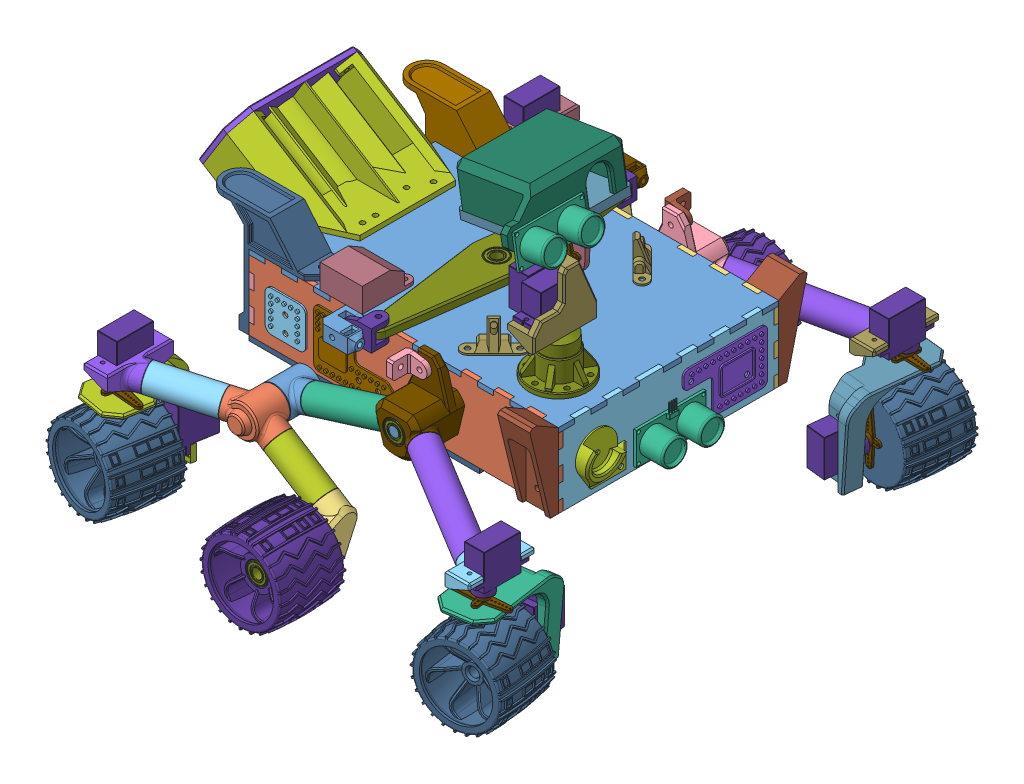
SolidWorks assembly full, configuration Default. Lengths in mm.
Overall size (307.73 234.76 324.89).
113 component instances, 62 part files, 10 mates.
Components (placement in the parent):
- bodySub-2-1: bodySub-2 [Default] at (-27.7012 6.4146 93.6508) size (271.51 168.8 196)
  - body-top-1: body-top [Default] at (-43.052 0 151.6865) x (1 0 0) z (0 1 0) size (191 136 3)
  - body-right-1: body-right [Default] at (-43.052 -43 148.6865) size (191 46 3)
  - body-left-1: body-left [Default] at (-43.052 -43 18.6865) x (-1 0 0) z (0 0 -1) size (191 46 3)
  - body-rear-1: body-rear [Default] at (-43.052 -43 15.6865) x (0 0 -1) z (1 0 0) size (136 46 3)
  - body-front-1: body-front [Default] at (147.948 -43 15.6865) x (0 0 1) z (-1 0 0) size (136 46 3)
  - usSensor-1: usSensor [Default] at (-46.052 -45.55 62.1865) x (0 0 1) z (0 -1 0) size (43 15.6 26)
  - usSensor-2: usSensor [Default] at (147.948 -21 62.1865) x (0 0 1) z (0 1 0) size (43 15.6 26)
  - power-1: power [Default] at (-43.052 -43 151.6865) x (0 0 1) z (-1 0 0) size (84 85.03 90.67)
  - powerCap-1: powerCap [Default] at (-74.8205 44.2822 15.6865) x (0 0 -1) z (-0.848048 0.529919 0) size (84 51.88 5)
  - powerShoulder-left-1: powerShoulder-left [Default] at (-43.052 -43 15.6865) x (-1 0 0) z (0 0 -1) size (66.06 69 21)
  - powerShoulder-right-1: powerShoulder-right [Default] at (-43.052 -43 109.6865) x (-1 0 0) z (0 0 -1) size (66.06 69 21)
  - shoulder-1: shoulder [Default] at (127.948 -43 151.6865) size (20 53.5 17.6)
  - shoulder-2: shoulder [Default] at (147.948 -43 15.6865) x (-1 0 0) z (0 0 -1) size (20 53.5 17.6)
  - headSub-1: headSub [Default] at (131.8571 34.2972 110.6077) size (71.32 113.8 76.5) (flexible)
    - headServoMount-1: headServoMount [Default] at (-5.7591 24.2018 7.3288) x (0 0 1) z (1 0 0) size (39.75 36.12 28.6)
    - headMount-1: headMount [Default] at (-19.6139 25.1697 -5.5142) x (0.16009 -0.987102 0) z (0 0 -1) size (40 30 34)
    - headBaseplate-1: headBaseplate [Default] at (-50.728 44.8869 -23.5142) x (0 0 1) z (-0.987102 -0.16009 0) size (60 5 50)
    - headCanopy-1: headCanopy [Default] at (-6.1756 82.5045 -23.5142) x (0 0 1) z (0.16009 -0.987102 0) size (76.5 50 25)
    - usSensor-2: usSensor [Default] at (-0.5725 47.9559 49.9858) x (0 0 -1) z (0.16009 -0.987102 0) size (43 15.6 26)
    - mastMount-top-1: mastMount-top [Default] at (-11.9091 -31.2972 13.0788) size (36 28 36)
    - sg90Servo-1: sg90Servo [Default] at (-5.7591 24.0708 7.3288) x (0 0 1) z (1 0 0) size (32.7 29.37 12.3)
    - sg90Servo-2: sg90Servo [Default] at (-18.0591 24.5458 25.4538) x (0 -1 0) z (1 0 0) size (32.7 29.37 12.3)
    - sg90ServoHorn-star-1: sg90ServoHorn-star [Default] at (-27.3265 20.2151 -5.5142) x (0.16009 -0.987102 0) z (-0.987102 -0.16009 0) size (34.4 4 15.7)
  - pivotAxle-1: pivotAxle [Default] at (76.448 -20 181.6865) x (-0.972905 0.231206 0) z (-0.231206 -0.972905 0) size (6 196 6)
  - edison-arduino-1: edison-arduino [Default] at (-30.752 -13.38 66.6865) x (1 0 0) z (0 0 -1) size (127.2 12.67 72)
  - diffMount-mid-1: diffMount-mid [Default] at (-43.052 0 151.6865) x (-1 0 0) z (0 -1 0) size (30 30 3)
  - diffMount-bottom-1: diffMount-bottom [Default] at (-43.052 -3 151.6865) x (-1 0 0) z (0 -1 0) size (30 30 3)
  - sideDetailA-left-1: sideDetailA-left [Default] at (-43.052 -43 15.6865) x (-1 0 0) z (0 0 -1) size (25 25 2)
  - sideDetailB-1: sideDetailB [Default] at (-43.052 -43 15.6865) x (-1 0 0) z (0 0 -1) size (55 35 2)
  - fontDetailA-1: fontDetailA [Default] at (147.948 -43 15.6865) x (0 0 -1) z (1 0 0) size (30.16 30.17 9.09)
  - frontDetailB-1: frontDetailB [Default] at (147.948 -43 15.6865) x (0 0 -1) z (1 0 0) size (51.58 33 2)
  - sideDetailB-mirr-1: sideDetailB-mirr [Default] at (-43.052 -43 151.6865) x (-1 0 0) z (0 0 -1) size (55 35 2)
  - sideDetailA-left-2: sideDetailA-left [Default] at (3.948 -43 151.6865) size (25 25 2)
  - bodyUnderCover-1: bodyUnderCover [Default] at (99.148 -43 15.6865) x (1 0 0) z (0 -1 0) size (142.2 136 9)
  - underCoverMagnetMount-front-1: underCoverMagnetMount-front [Default] at (99.148 -43 15.6865) x (-1 0 0) z (0 1 0) size (7 7 11.3)
  - underCoverMagnetMount-front-2: underCoverMagnetMount-front [Default] at (89.148 -43 151.6865) x (1 0 0) z (0 1 0) size (7 7 11.3)
  - underCoverMagnetMount-front-3: underCoverMagnetMount-front [Default] at (-31.552 -43 15.6865) x (-1 0 0) z (0 1 0) size (7 7 11.3)
  - underCoverMagnetMount-front-4: underCoverMagnetMount-front [Default] at (-41.552 -43 151.6865) x (1 0 0) z (0 1 0) size (7 7 11.3)
  - topDetailA-1: topDetailA [Default] at (-43.052 3 151.6865) x (1 0 0) z (0 1 0) size (24.26 24.26 16)
  - topDetailA-2: topDetailA [Default] at (108.7154 3 168.7548) x (0 0 -1) z (0 1 0) size (24.26 24.26 16)
  - topDetailB-1: topDetailB [Default] at (-43.052 3 151.6865) x (1 0 0) z (0 1 0) size (26 34 15)
  - topDetailCA-1: topDetailCA [Default] at (-46.5393 3 149.9052) x (1 0 0) z (0 1 0) size (20.56 18.54 22.66)
  - topDetailCB-1: topDetailCB [Default] at (1.7026 61.1918 61.409) x (0.910046 -0.22774 0.34634) z (0.414508 0.5 -0.760384) size (46.65 24.53 4)
- diffSub-1: diffSub [Default] at (-10.0363 9.4146 112.9319) size (33.52 13 184.66) (flexible)
  - differentialBar-1: differentialBar [Default] at (-60.7169 0 132.4054) x (1 0 0) z (0 1 0) size (30 156 5)
  - differentialHinge-1: differentialHinge [Default] at (109.2895 6 -3.7047) x (-0.999999 0 0.001295) z (0 1 0) size (18.65 13.57 13)
  - rodHinge-diff-left-1: rodHinge-diff-left [Default] at (109.2895 0 -2.6005) size (21.11 9.1 17.1)
  - rodHinge-diff-right-1: rodHinge-diff-right [Default] at (109.2895 0 147.4113) size (21.11 9.1 17.1)
  - differentialHinge-2: differentialHinge [Default] at (109.2895 -1 132.5155) x (-0.999999 0 -0.001295) z (0 -1 0) size (18.65 13.57 13)
- suspensionSub-left[moving]-1: suspensionSub-left[moving] [Default] at (56.8042 -47.8978 160.4829) x (0 0 1) z (-1 0 0) size (94.09 136.27 295.91) (flexible)
  - bogieJointFixed-left-1: bogieJointFixed-left [Default] at (-58.6456 10.5337 84.2533) x (0 0.297904 -0.954596) z (1 0 0) size (40 20 21.53)
  - bogieJointFree-left-1: bogieJointFree-left [Default] at (-79.1456 10.5337 84.2533) x (1 0 0) z (0 0.534644 0.845077) size (27.04 27.37 57.25)
  - rockerJoint-left-1: rockerJoint-left [Default] at (-51.1456 34.3124 8.0574) x (1 0 0) z (0 -0.297904 0.954596) size (35.64 50.55 55.79)
  - aftBogieTube-1: aftBogieTube [Default] at (-108.56 15.1077 132.4165) x (0.903071 0.263736 0.338977) z (-0.213924 0.960596 -0.177459) size (15.88 37.13 15.88)
  - aftRockerTube-1: aftRockerTube [Default] at (-68.6456 15.0022 69.9343) x (0.5 -0.826704 -0.257992) z (0.866025 0.477298 0.148952) size (15.88 49.82 15.88)
  - foreBogieTube-1: foreBogieTube [Default] at (-89.1456 2.514 71.5771) x (0.998082 0.052308 -0.033093) z (-0.061898 0.843457 -0.533619) size (15.88 33.7 15.88)
  - foreRockerTube-1: foreRockerTube [Default] at (-106.955 16.1877 -66.6715) x (0.694727 -0.694339 -0.187745) z (-0.564363 -0.688029 0.456191) size (15.88 70.91 15.88)
  - wheelStrut-mid-right-1: wheelStrut-mid-right [Default] at (-119.2029 -30.2767 38.8726) size (23.13 36.67 28.96)
  - tire-1: tire [Default] at (-113.6439 -30.2768 -79.7193) x (-0.019946 0.98253 0.185032) z (-0.99424 0 -0.107176) size (53.45 55.85 40.12)
  - tire-3: tire [Default] at (-114.1463 -30.2762 146.2751) x (0.027949 0.973072 0.2288) z (-0.992622 0 0.121254) size (53.45 55.85 40.12)
  - rodHinge-sus-left-1: rodHinge-sus-left [Default] at (-62.1456 34.3124 8.0574) x (0 0.297904 -0.954596) z (1 0 0) size (15.98 12.99 13)
  - sg90ServoHorn-star-1: sg90ServoHorn-star [Default] at (-111.014 4.7232 -77.5248) x (0.107176 0 -0.99424) z (0.99424 0 0.107176) size (34.4 4 15.7)
  - sg90ServoHorn-star-2: sg90ServoHorn-star [Default] at (-117.2057 4.7238 144.7347) x (0.121254 0 0.992622) z (-0.992622 0 0.121254) size (34.4 4 15.7)
  - sg90ServoHorn-star-3: sg90ServoHorn-star [Default] at (-93.9356 -28.5447 146.7837) x (-0.007036 -0.998315 -0.057599) z (0.121049 -0.058027 0.990949) size (34.4 4 15.7)
  - sg90ServoHorn-star-4: sg90ServoHorn-star [Default] at (-94.0671 -28.4131 -74.7185) x (0.001357 -0.99992 -0.012589) z (-0.107167 -0.012662 0.99416) size (34.4 4 15.7)
  - sg90Servo-1: sg90Servo [Default] at (-119.8963 35.6918 140.1251) x (1 0 0) z (0 0 -1) size (32.7 29.37 12.3)
  - sg90Servo-2: sg90Servo [Default] at (-62.8087 -36.0262 146.1996) x (0 1 0) z (0.121254 0 0.992622) size (32.7 29.37 12.3)
  - sg90Servo-3: sg90Servo [Default] at (-63.6286 -36.0268 -68.1422) x (0 1 0) z (-0.107176 0 0.99424) size (32.7 29.37 12.3)
  - sg90Servo-4: sg90Servo [Default] at (-119.3939 35.6912 -85.8693) x (1 0 0) z (0 0 -1) size (32.7 29.37 12.3)
  - wheelPivot-front-left-v2-1: wheelPivot-front-left-v2 [Default] at (-119.3939 35.6912 -67.5693) x (1 0 0) z (0 0 -1) size (40.7 16.47 34.17)
  - wheelPivot-rear-left-v2-1: wheelPivot-rear-left-v2 [Default] at (-119.8963 35.6918 134.1251) x (-1 0 0) z (0 0 1) size (40.7 18.75 35.49)
  - wheelStrut-front-left-v2-1: wheelStrut-front-left-v2 [Default] at (-64.9469 -36.0268 -55.913) x (0 1 0) z (-0.107176 0 0.99424) size (50.75 59.16 31.22)
  - wheelStrut-rear-left-v2-1: wheelStrut-rear-left-v2 [Default] at (-65.7915 -36.0262 121.7812) x (0 1 0) z (0.121254 0 0.992622) size (50.75 59.16 31.22)
  - 6x13x5BearingShielded-1: 6x13x5BearingShielded [Default] at (-56.1456 34.3124 8.0574) x (0 -0.920758 0.390135) z (0 0.390135 0.920758) size (13 5 13)
  - 6x13x5BearingShielded-2: 6x13x5BearingShielded [Default] at (-76.1456 34.3124 8.0574) x (0 1 0) z (0 0 1) size (13 5 13)
  - 6x13x5BearingShielded-3: 6x13x5BearingShielded [Default] at (-73.6456 10.5337 84.2533) x (0 1 0) z (0 0 1) size (13 5 13)
  - 6x13x5BearingShielded-4: 6x13x5BearingShielded [Default] at (-63.6456 10.5337 84.2533) x (0 -1 0) z (0 0 1) size (13 5 13)
  - tire-mid-1: tire-mid [Default] at (-125.1743 -30.2767 38.8726) x (0 0.956404 0.292046) z (-1 0 0) size (53.45 55.85 40.12)
  - 6x13x5BearingShielded-5: 6x13x5BearingShielded [Default] at (-110.1743 -30.2767 38.8726) x (0 -1 0) z (0 0 1) size (13 5 13)
  - 6x13x5BearingShielded-6: 6x13x5BearingShielded [Default] at (-135.1743 -30.2767 38.8726) x (0 -1 0) z (0 0 1) size (13 5 13)
- suspensionSub-right[moving]-1: suspensionSub-right[moving] [Default] at (87.723 -47.5963 248.1372) x (0 0 1) z (-1 0 0) size (94.8 134.78 293.57) (flexible)
  - rockerJoint-right-1: rockerJoint-right [Default] at (-2.7999 34.0109 38.9762) x (1 0 0) z (0 -0.297904 0.954596) size (35.64 50.55 55.79)
  - bogieJointFixed-right-1: bogieJointFixed-right [Default] at (4.7001 10.2319 115.1719) x (0 0.297904 -0.954596) z (1 0.000024 0.000007) size (40 20 21.53)
  - bogieJointFree-right-1: bogieJointFree-right [Default] at (25.2001 10.2324 115.1721) x (1 0.000024 0.000007) z (-0.000019 0.534634 0.845084) size (27.04 27.37 57.25)
  - wheelStrut-mid-left-1: wheelStrut-mid-left [Default] at (35.3591 -30.5762 69.7903) x (0.999881 0.013057 -0.008238) z (0.008238 0.000041 0.999966) size (23.13 36.67 28.96)
  - aftBogieTube-1: aftBogieTube [Default] at (54.614 14.8065 163.3356) x (0.909042 0.166055 -0.38219) z (-0.186953 0.982205 -0.017918) size (15.88 37.13 15.88)
  - aftRockerTube-1: aftRockerTube [Default] at (14.7001 14.7007 100.8531) x (1 0.000024 0.000007) z (-0.000025 0.954596 0.297904) size (15.88 49.82 15.88)
  - foreBogieTube-1: foreBogieTube [Default] at (35.201 -15.804 74.0166) x (0.998959 -0.038532 0.024399) z (-0.045607 -0.844205 0.534077) size (15.88 33.7 15.88)
  - foreRockerTube-1: foreRockerTube [Default] at (53.0095 15.8862 -35.7528) x (0.835794 0.445925 0.320312) z (0.320312 -0.869851 0.375178) size (15.88 70.91 15.88)
  - tire-1: tire [Default] at (60.1999 -30.5774 177.1942) x (0.036514 -0.976378 -0.212962) z (0.985612 -0.000007 0.169026) size (53.45 55.85 40.12)
  - tire-3: tire [Default] at (59.6984 -30.5783 -48.8006) x (0.005902 -0.999154 0.040692) z (0.989645 0 -0.143534) size (53.45 55.85 40.12)
  - rodHinge-sus-1: rodHinge-sus [Default] at (8.2001 34.0109 38.9762) x (0 0.297904 -0.954596) z (1 0 0) size (15.98 12.99 13)
  - sg90ServoHorn-star-1: sg90ServoHorn-star [Default] at (40.2747 -32.8405 -43.3845) x (0.019091 0.991115 0.131631) z (0.142259 -0.133008 0.980852) size (34.4 4 15.7)
  - sg90Servo-1: sg90Servo [Default] at (11.0047 -36.327 162.5178) x (0.000007 1 0) z (0.169026 -0.000001 -0.985612) size (32.7 29.37 12.3)
  - sg90Servo-2: sg90Servo [Default] at (65.4484 35.3897 -42.6506) x (-1 0 0) z (0 0 1) size (32.7 29.37 12.3)
  - sg90Servo-3: sg90Servo [Default] at (8.3754 -36.3283 -47.5712) x (0 1 0) z (-0.143534 0 -0.989645) size (32.7 29.37 12.3)
  - sg90Servo-4: sg90Servo [Default] at (65.9503 35.3906 183.3443) x (-1 0.000007 -0.00001) z (-0.00001 0 1) size (32.7 29.37 12.3)
  - wheelPivot-front-right-v2-1: wheelPivot-front-right-v2 [Default] at (65.4484 35.3897 -42.6506) x (-1 0 0) z (0 0 1) size (40.7 16.47 34.17)
  - wheelStrut-front-right-v2-1: wheelStrut-front-right-v2 [Default] at (8.3754 -36.3283 -47.5712) x (0 1 0) z (-0.143534 0 -0.989645) size (50.75 59.16 31.22)
  - sg90ServoHorn-star-2: sg90ServoHorn-star [Default] at (62.7916 4.4217 -47.3293) x (-0.143534 0 -0.989645) z (0.989645 0 -0.143534) size (34.4 4 15.7)
  - sg90ServoHorn-star-3: sg90ServoHorn-star [Default] at (40.1653 -33.4225 175.6933) x (-0.064618 0.924024 0.376834) z (-0.156187 -0.382334 0.910729) size (34.4 4 15.7)
  - sg90ServoHorn-star-4: sg90ServoHorn-star [Default] at (57.7123 4.4227 174.8398) x (-0.169026 0.000001 0.985612) z (-0.985612 0.000007 -0.169026) size (34.4 4 15.7)
  - wheelStrut-rear-right-v2-1: wheelStrut-rear-right-v2 [Default] at (8.9257 -36.327 174.6408) x (0.000007 1 0) z (0.169026 -0.000001 -0.985612) size (50.75 59.16 31.22)
  - wheelPivot-rear-right-v2-1: wheelPivot-rear-right-v2 [Default] at (65.9504 35.3906 171.0443) x (1 -0.000007 0.00001) z (0.00001 0 -1) size (40.7 18.75 35.49)
  - 6x13x5BearingShielded-1: 6x13x5BearingShielded [Default] at (22.2001 34.0109 38.9762) x (0 -1 0) z (0 0 1) size (13 5 13)
  - 6x13x5BearingShielded-2: 6x13x5BearingShielded [Default] at (2.2001 34.0109 38.9762) x (0 1 0) z (0 0 1) size (13 5 13)
  - 6x13x5BearingShielded-3: 6x13x5BearingShielded [Default] at (24.7001 10.2324 115.1721) x (-0.000024 1 0) z (-0.000007 0 1) size (13 5 13)
  - 6x13x5BearingShielded-4: 6x13x5BearingShielded [Default] at (9.7001 10.232 115.172) x (-0.000024 1 0) z (-0.000007 0 1) size (13 5 13)
  - tire-mid-1: tire-mid [Default] at (71.3835 -30.1057 69.4935) x (-0.008066 -0.013171 -0.999881) z (0.999881 0.013057 -0.008238) size (53.45 55.85 40.12)
  - 6x13x5BearingShielded-5: 6x13x5BearingShielded [Default] at (56.3852 -30.3016 69.6171) x (0.013164 -0.999828 0.013064) z (-0.008066 -0.013171 -0.999881) size (13 5 13)
  - 6x13x5BearingShielded-6: 6x13x5BearingShielded [Default] at (76.3829 -30.0405 69.4524) x (0.013164 -0.999828 0.013064) z (0.008066 0.013171 0.999881) size (13 5 13)
- 6x13x5BearingShielded-1: 6x13x5BearingShielded [Default] at (14.2468 14.4146 177.3373) x (0 0 -1) z (-1 0 0) size (13 5 13)
Mates (geometry in assembly coordinates):
- Coincident7: coincident: point of bodySub-2-1/body-top-1; point of diffSub-1/differentialBar-1
- Coincident8: coincident anti-aligned: plane of bodySub-2-1/body-top-1 through (-70.7532 9.4146 245.3373) normal (0 1 0); plane of diffSub-1/differentialBar-1 through (-70.7532 9.4146 245.3373) normal (0 -1 0)
- Coincident9: coincident anti-aligned: plane of bodySub-2-1/body-left-1 through (-70.7532 -36.5854 109.3373) normal (0 0 -1); plane of suspensionSub-left[moving]-1/rockerJoint-left-1 through (48.7468 -13.5854 109.3373) normal (0 0 1)
- Coincident10: coincident: point of bodySub-2-1/body-left-1; point of suspensionSub-left[moving]-1/rockerJoint-left-1
- Coincident11: coincident anti-aligned: plane of bodySub-2-1/body-right-1 through (-70.7532 -36.5854 245.3373) normal (0 0 1); plane of suspensionSub-right[moving]-1/rockerJoint-right-1 through (48.7468 -13.5854 245.3373) normal (0 0 -1)
- Coincident12: coincident: point of bodySub-2-1/body-right-1; point of suspensionSub-right[moving]-1/rockerJoint-right-1
- Concentric2: concentric anti-aligned: cylinder of diffSub-1/differentialBar-1 through (14.2468 14.4156 177.3373) axis (0 -1 0) radius 6.5; cylinder of 6x13x5BearingShielded-1 through (14.2468 9.4146 177.3373) axis (0 1 0) radius 6.5
- Coincident15: coincident anti-aligned: plane of bodySub-2-1/body-top-1 through (-70.7532 9.4146 245.3373) normal (0 1 0); plane of 6x13x5BearingShielded-1 through (14.2468 9.4146 177.3373) normal (0 -1 0)
- Distance1: distance = 20.7769 mm anti-aligned: plane of suspensionSub-right[moving]-1/rodHinge-sus-1 through (38.0159 -13.5854 259.3373) normal (-1 0 0); plane of diffSub-1/rodHinge-diff-right-1 through (17.239 11.9146 264.8932) normal (1 0 0)
- Distance2: distance = 20.7769 mm anti-aligned: plane of diffSub-1/rodHinge-diff-left-1 through (17.239 11.9146 89.7814) normal (1 0 0); plane of suspensionSub-left[moving]-1/rodHinge-sus-left-1 through (38.0159 -13.5854 95.3373) normal (-1 0 0)
